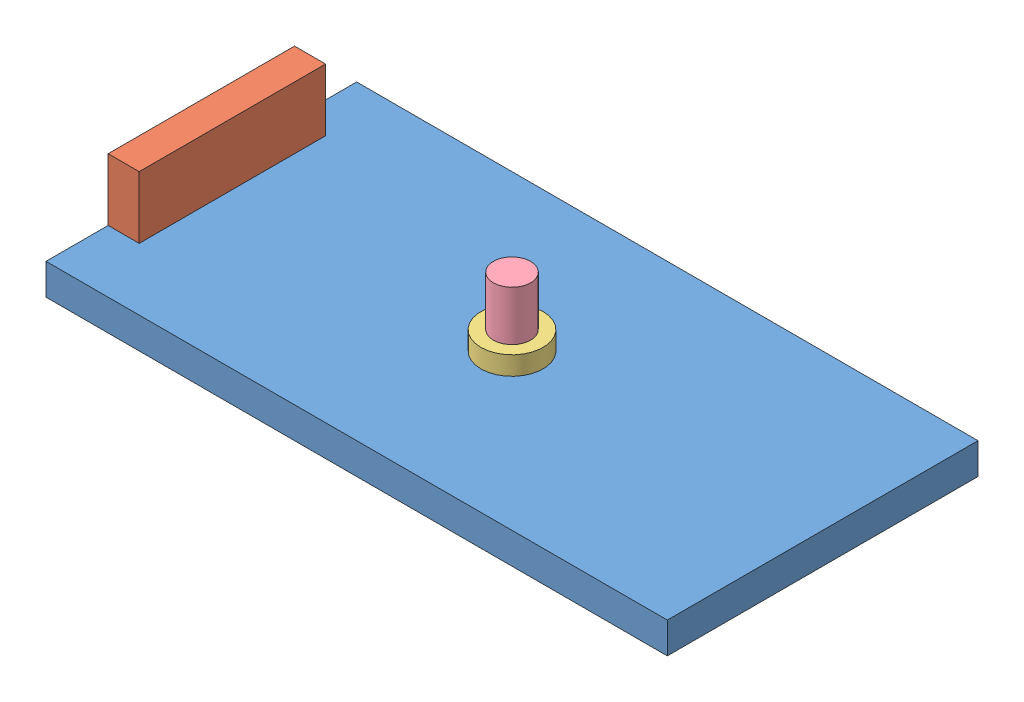
SolidWorks assembly Assem, configuration Default. Lengths in mm.
Overall size (1000 160 500).
5 component instances, 4 part files, 9 mates.
Components (placement in the parent):
- part1-1: part1 [Default] at origin size (1000 50 500)
- part2-1: part2 [Default] at (-475 50 0) size (50 100 300)
- SubAssem-1: SubAssem [Default] at (0 50 0) size (100 110 100)
  - subpart1-1: subpart1 [Default] at origin size (100 30 100)
  - subpart2-1: subpart2 [Default] at (0 30 0) size (60 80 60)
Mates (geometry in assembly coordinates):
- 重合1: coincident aligned: plane of part1-1 through (0 0 0) normal (0 0 1)
- 重合2: coincident aligned: plane of part1-1 through (0 0 0) normal (0 1 0)
- 重合3: coincident aligned: plane of part1-1 through (0 0 0) normal (1 0 0)
- 重合4: coincident anti-aligned: plane of part1-1 through (0 50 0) normal (0 1 0); plane of part2-1 through (-475 50 0) normal (0 -1 0)
- 重合5: coincident aligned: plane of part1-1 through (0 0 0) normal (0 0 1); plane of part2-1 through (-475 50 0) normal (0 0 1)
- 重合6: coincident aligned: plane of part1-1 through (-500 50 250) normal (-1 0 0); plane of part2-1 through (-500 150 150) normal (-1 0 0)
- 重合7: coincident aligned: plane of SubAssem-1 through (0 152.0698 0) normal (0 0 1)
- 重合8: coincident aligned: plane of SubAssem-1 through (0 152.0698 0) normal (1 0 0)
- 重合9: coincident anti-aligned: plane of part1-1 through (0 50 0) normal (0 1 0); plane of SubAssem-1/subpart1-1 through (0 50 0) normal (0 -1 0)
